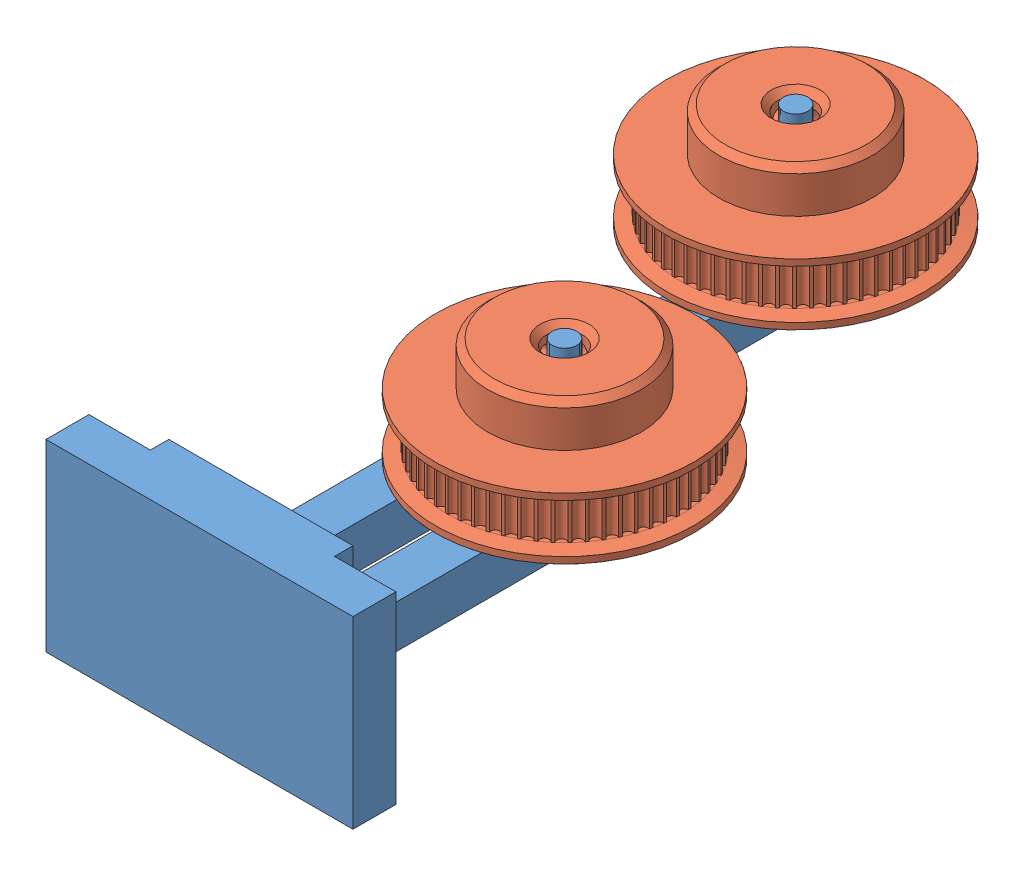
SolidWorks assembly Assem2, configuration Default. Lengths in mm.
Overall size (61.13 33.65 127.91).
3 component instances, 2 part files, 4 mates.
Components (placement in the parent):
- upper mount for pulley-1: upper mount for pulley [Default] at (7.9776 22.556 46.421) size (50 33.65 110)
- Poulie GT2 60 dents-1: Poulie GT2 60 dents [Défaut] at (14.5985 29.2072 0.5832) x (0.990325 0 -0.138769) z (0 -1 0) size (42 42 17)
- Poulie GT2 60 dents-2: Poulie GT2 60 dents [Défaut] at (0.3943 29.2072 -51.2751) x (0.99373 0 0.111807) z (0 -1 0) size (42 42 17)
Mates (geometry in assembly coordinates):
- Concentric1: concentric: circle of upper mount for pulley-1; circle of Poulie GT2 60 dents-1
- Coincident3: coincident: plane of upper mount for pulley-1 through (14.5985 41.2072 0.5832) normal (0 1 0); plane of Poulie GT2 60 dents-1 through (14.5985 41.2072 0.5832) normal (0 1 0)
- Concentric2: concentric: circle of upper mount for pulley-1; circle of Poulie GT2 60 dents-2
- Coincident4: coincident: plane of upper mount for pulley-1 through (0.3943 41.2072 -51.2751) normal (0 1 0); plane of Poulie GT2 60 dents-2 through (0.3943 41.2072 -51.2751) normal (0 1 0)
